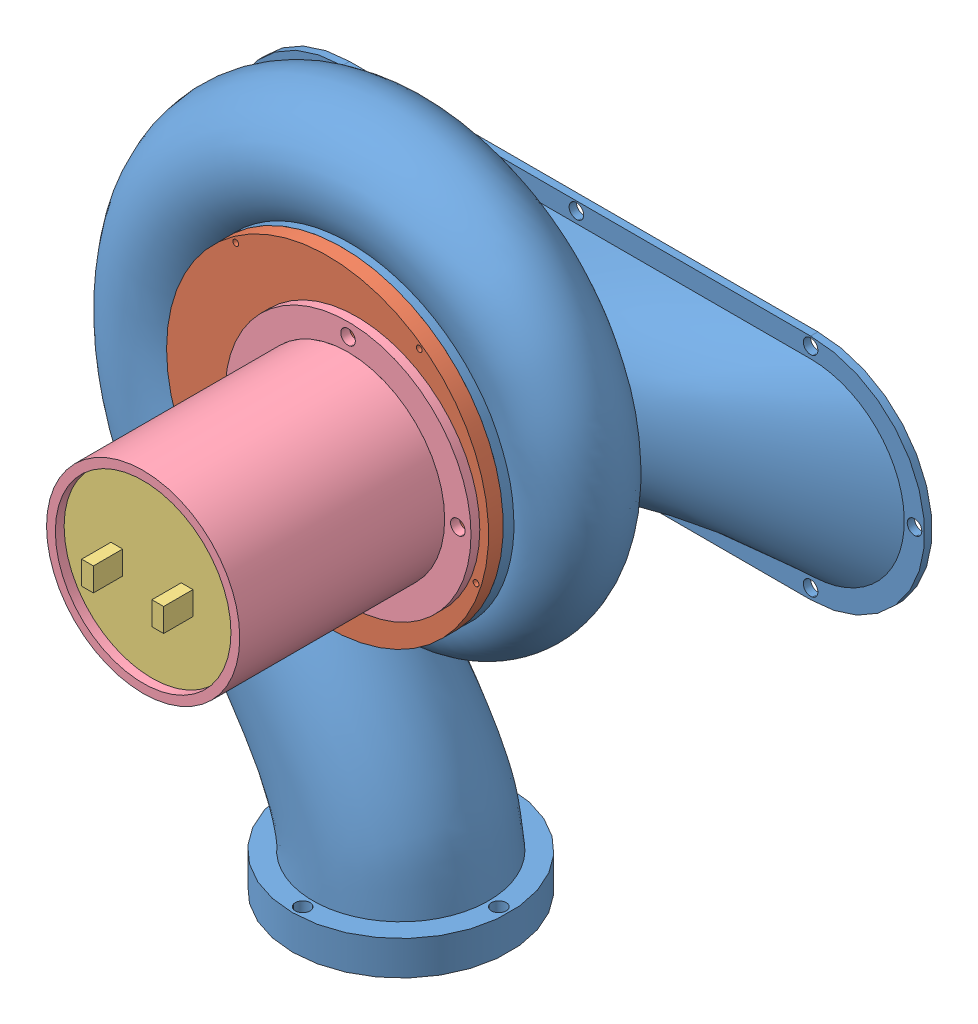
SolidWorks assembly Centrifugal Pump Assembly (partial), configuration Default. Lengths in mm.
Overall size (119 116.73 78.75).
4 component instances, 4 part files, 12 mates.
Components (placement in the parent):
- Centrifugal Pump Casing-1: Centrifugal Pump Casing [Default] x (1 0 0) z (0 0 -1) size (119 116.73 44.75)
- Centrifugal Pump Casing Cover-2: Centrifugal Pump Casing Cover [Default] at (-0.0001 0 11.25) x (1 0 0) z (0 0 -1) size (55 55 2.5)
- Centrifugal Pump Motor-1: Centrifugal Pump Motor [Default] at (4.9999 0 47.5) x (1 0 0) z (0 0 -1) size (30 30 45)
- Motor Cover-1: Motor Cover [Default] at (4.9999 0 16) size (42 42 36.5)
Mates (geometry in assembly coordinates):
- Coincident2: coincident anti-aligned: plane of Centrifugal Pump Casing-1 through (0 0 0) normal (0 0 -1)
- Coincident3: coincident anti-aligned: plane of Centrifugal Pump Casing-1 through (0 0 0) normal (0 -1 0)
- Coincident4: coincident aligned: plane of Centrifugal Pump Casing-1 through (0 0 0) normal (1 0 0)
- Concentric2: concentric anti-aligned: cylinder of Centrifugal Pump Casing-1 through (15.6743 21.5738 10) axis (0 0 1) radius 0.5; cylinder of Centrifugal Pump Casing cover-2 through (15.6742 21.5738 10) axis (0 0 -1) radius 0.5
- Concentric3: concentric anti-aligned: cylinder of Centrifugal Pump Casing-1 through (-25.3616 -8.2405 10) axis (0 0 1) radius 0.5; cylinder of Centrifugal Pump Casing cover-2 through (-25.3616 -8.2405 10) axis (0 0 -1) radius 0.5
- Coincident6: coincident anti-aligned: plane of Centrifugal Pump Casing-1 through (0 0 10) normal (0 0 1); plane of Centrifugal Pump Casing cover-2 through (-0.0001 0 10) normal (0 0 -1)
- Concentric4: concentric: cylinder of Centrifugal Pump Motor-1 through (4.9999 0 17.5) axis (0 0 1) radius 15; cylinder of Motor Cover-1 through (4.9999 0 17.5) axis (0 0 -1) radius 2.5
- Coincident7: coincident: plane of Centrifugal Pump Motor-1 through (4.9999 0 17.5) normal (0 0 -1); plane of Motor Cover-1 through (4.9999 0 17.5) normal (0 0 1)
- Concentric5: concentric anti-aligned: cylinder of Centrifugal Pump Casing cover-2 through (4.9999 0 12.5) axis (0 0 -1) radius 2.5; cylinder of Centrifugal Pump Motor-1 through (4.9999 0 7.5) axis (0 0 1) radius 1.5
- Parallel2: parallel aligned: plane of Centrifugal Pump Casing-1 through (45 -19.6271 -26.25) normal (0 -1 0); plane of Centrifugal Pump Motor-1 through (11.9999 -2.3766 52.5) normal (0 -1 0)
- Coincident9: coincident: plane of Centrifugal Pump Casing cover-2 through (-0.0001 0 12.5) normal (0 0 1); plane of Motor Cover-1 through (4.9999 0 12.5) normal (0 0 -1)
- Concentric8: concentric anti-aligned: cylinder of Centrifugal Pump Casing cover-2 through (23.7499 0 12.5) axis (0 0 -1) radius 1.25; cylinder of Motor Cover-1 through (23.7499 0 12.5) axis (0 0 1) radius 1.25
